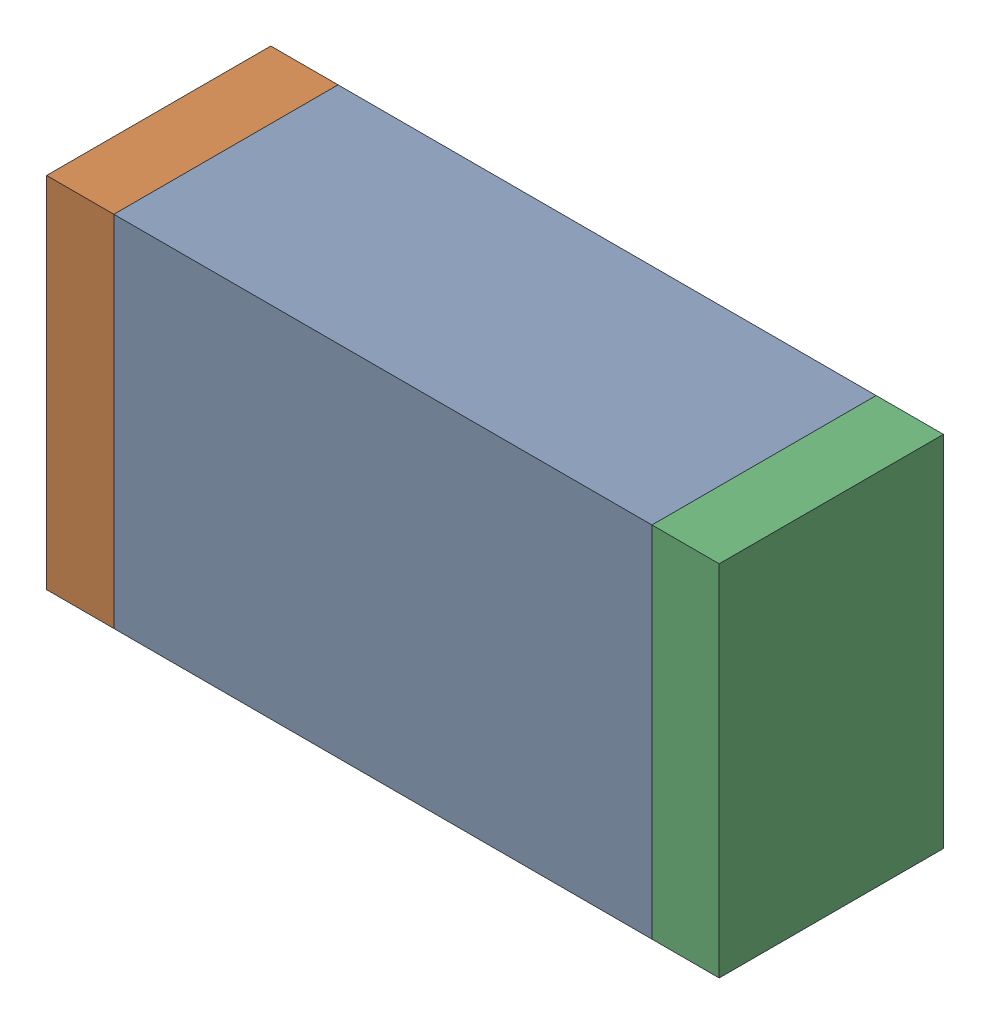
SolidWorks assembly C8, configuration Default. Lengths in mm.
Overall size (1.5 0.8 0.5).
6 component instances, 2 part files, 0 mates.
Components (placement in the parent):
- 836752368-1: 836752368 [Default] at (133.75 8.2 0) size (1.2 0.8 0.5)
  - Extruded-1: Extruded [Default] at origin size (1.2 0.8 0.5)
- 836752496-1: 836752496 [Default] at (133.075 8.2 0) size (0.15 0.8 0.5)
  - Extruded_2-1: Extruded_2 [Default] at origin size (0.15 0.8 0.5)
- 836752496-2: 836752496 [Default] at (134.425 8.2 0) size (0.15 0.8 0.5)
  - Extruded_2-1: Extruded_2 [Default] at origin size (0.15 0.8 0.5)
